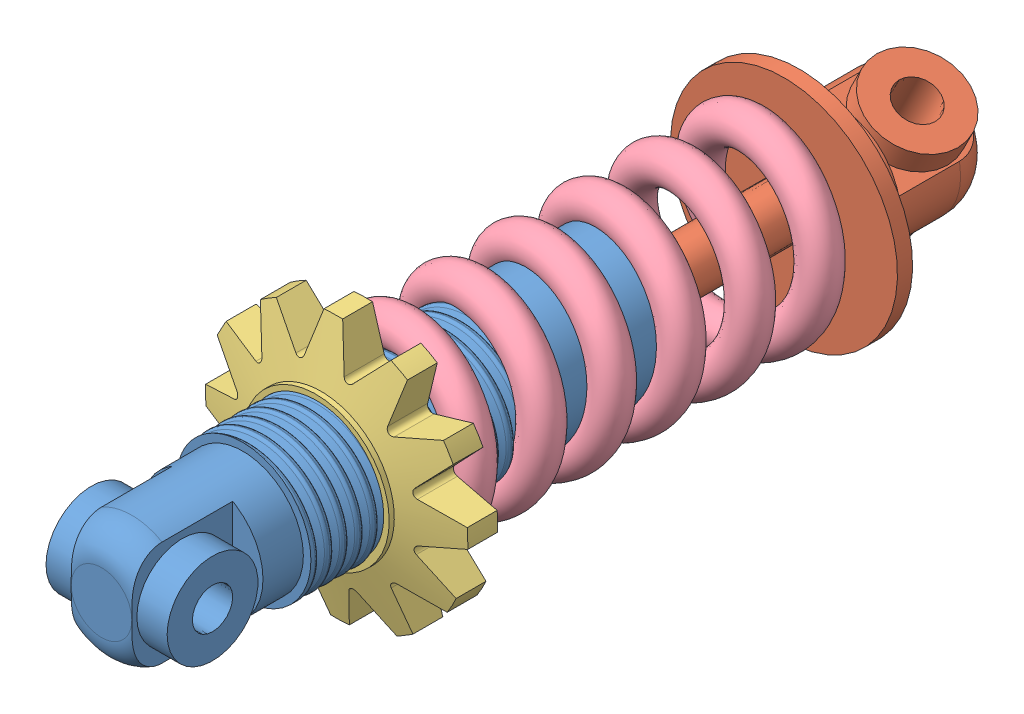
SolidWorks assembly Montaj1, configuration Varsayılan. Lengths in mm.
Overall size (72.18 72.18 167.55).
4 component instances, 4 part files, 6 mates.
Components (placement in the parent):
- top rod-1: top rod [Varsayılan] at (-1.1226 -52.4632 72.4163) size (27.91 28.17 110.25)
- base-1: base [Varsayılan] at (-1.1226 -52.4632 43.1228) x (0.450581 0.892735 0) z (0 0 1) size (45 45 101)
- nut-1: nut [Varsayılan] at (-1.1226 -52.4632 128.8316) x (0.724851 -0.688905 0) z (-0.688905 -0.724851 0) size (51.06 11.86 51.06)
- spring-1: spring [Varsayılan] at (-1.1226 -52.4632 46.1228) x (-0.852724 -0.522361 0) z (0.522361 -0.852724 0) size (38.32 89.96 37.25)
Mates (geometry in assembly coordinates):
- Eş Merkezli1: concentric aligned: cylinder of top rod-1 through (-1.1226 -52.4632 147.4163) axis (0 0 -1) radius 5; cylinder of base-1 through (-1.1226 -52.4632 116.1228) axis (0 0 -1) radius 5
- Eş Merkezli2: concentric aligned: cylinder of top rod-1 through (-1.1226 -52.4632 153.3463) axis (0 0 -1) radius 13.5; cylinder of nut-1 through (-1.1226 -52.4632 138.8316) axis (0 0 -1) radius 14.5
- Vida1: screw = 1 aligned: line of top rod-1 through (-1.1226 -52.4632 104.1622) axis (0 0 -1); cylinder of nut-1 through (-1.1226 -52.4632 138.8316) axis (0 0 -1) radius 14.5
- Çakışık1: coincident anti-aligned: line of top rod-1 through (-1.1226 -52.4632 104.1622) axis (0 0 -1); line of spring-1 through (-1.1226 -52.4632 46.1228) axis (0 0 1)
- Çakışık2: coincident anti-aligned: plane of nut-1 through (-1.1226 -52.4632 128.8316) normal (0 0 -1); plane of spring-1 through (35.3606 -51.9561 128.8316) normal (0 0 1)
- Çakışık3: coincident anti-aligned: plane of base-1 through (-1.1226 -52.4632 46.1228) normal (0 0 1); plane of spring-1 through (-1.1226 -52.4632 46.1228) normal (0 0 -1)
